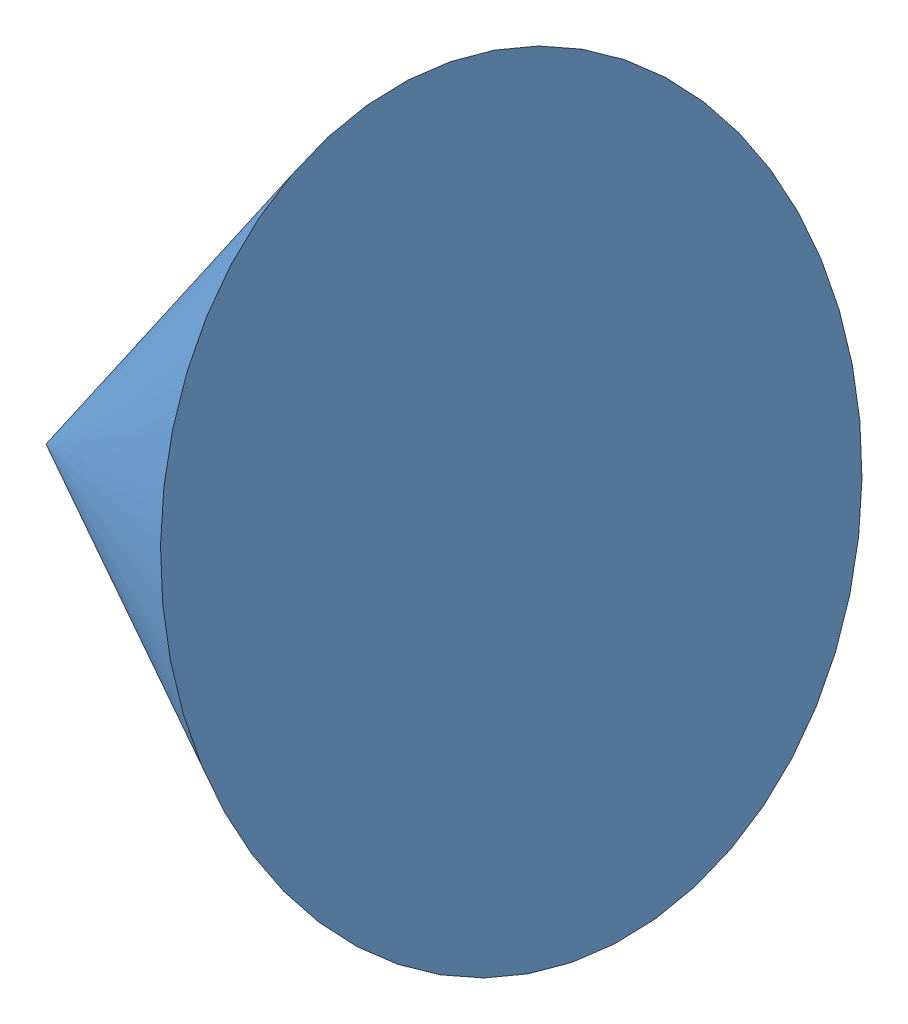
SolidWorks assembly assemply_final, configuration Default. Lengths in mm.
Overall size (338.1 186.15 159.49).
2 component instances, 2 part files, 2 mates.
Components (placement in the parent):
- path-1: path [Default] at (-12.5104 132.8868 230.2965) size (310.19 78.6 0)
- Part1-1: Part1 [Default] at (297.6762 172.1693 230.2965) x (-0.346006 0.926061 0.150637) z (0.052723 -0.141109 0.988589) size (140 105 140)
Mates (geometry in assembly coordinates):
- PathMate1: path: point of Part1-1; curve of path-1
- Coincident1: coincident: point of assembly; curve of path-1; point of Part1-1
